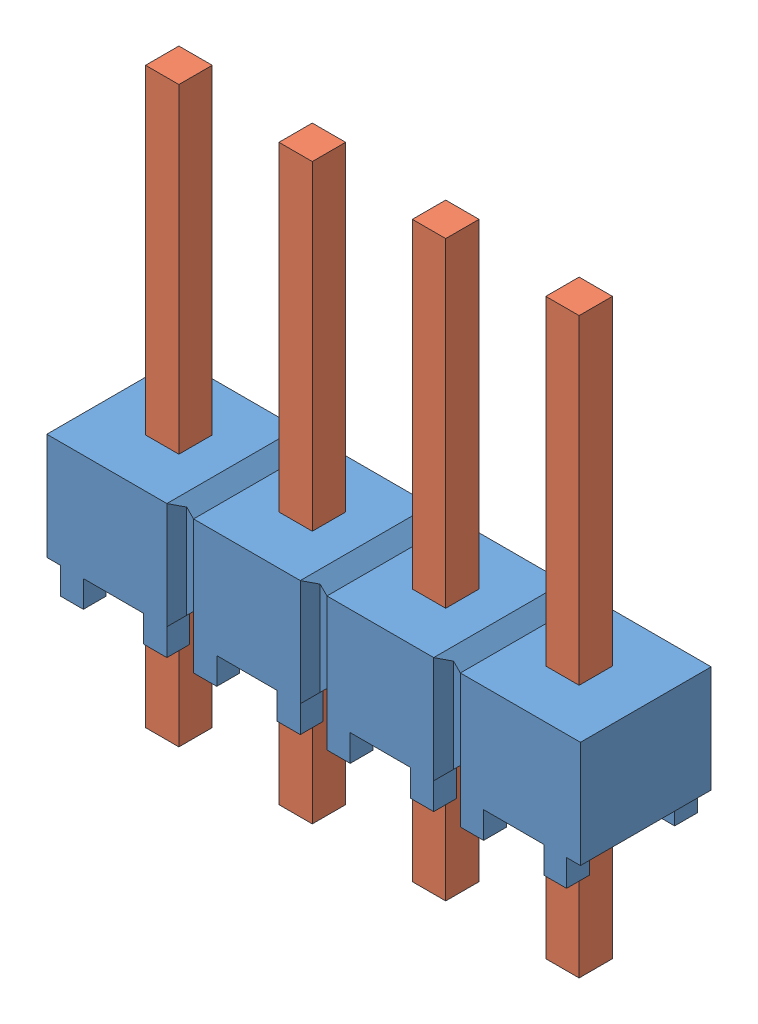
SolidWorks assembly HMTSW_104_07_G_S_240, configuration Default. Lengths in mm.
Overall size (10.16 10.92 2.49).
2 component instances, 2 part files, 0 mates.
Components (placement in the parent):
- _HMTSW_104_07_G_S_240_body_2-1: _HMTSW_104_07_G_S_240_body_2 [Default] at origin size (10.16 2.54 2.49)
- _HMTSW_104_07_S_240_4-1: _HMTSW_104_07_S_240_4 [Default] at (0 -2.286 0) size (8.51 10.92 0.89)
